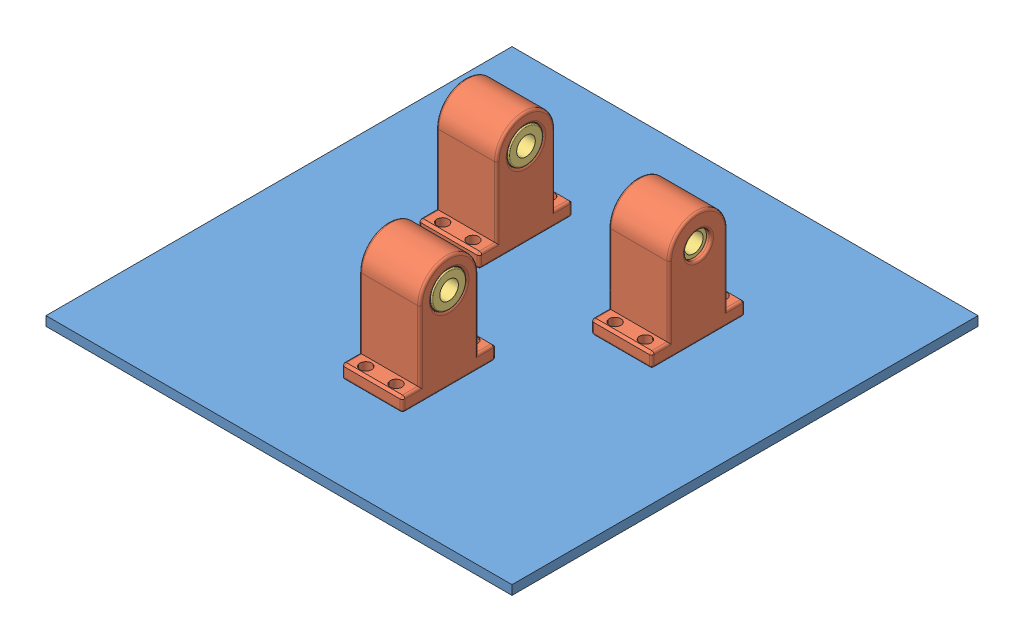
SolidWorks assembly millingBed, configuration Default. Lengths in mm.
Overall size (200 52.5 200).
10 component instances, 3 part files, 11 mates.
Components (placement in the parent):
- MillingBed-1: MillingBed [Default] at (-140.9841 198 101.9923) size (200 4 200)
- lm8uu+Holder-1: lm8uu+Holder [Default] at (-52.4841 225.3393 -25.132) x (1 0 0) z (0 0 -1) size (26.01 48.5 40.01)
  - lm8uu_Bearing_Holder-1: lm8uu_Bearing_Holder [Default] at (35.5 -12.6607 2.8758) size (26.01 48.5 40.01)
  - lm8uu_Bearing-1: lm8uu_Bearing [Default] at (35.5 -12.6607 2.8758) x (0 0 -1) z (0 -1 0) size (15 24 15)
- lm8uu+Holder-7: lm8uu+Holder [Default] at (-29.4841 225.3393 -30.8835) x (-1 0 0) z (0 0 1) size (26.01 48.5 40.01)
  - lm8uu_Bearing_Holder-1: lm8uu_Bearing_Holder [Default] at (35.5 -12.6607 2.8758) size (26.01 48.5 40.01)
  - lm8uu_Bearing-1: lm8uu_Bearing [Default] at (35.5 -12.6607 2.8758) x (0 0 -1) z (0 -1 0) size (15 24 15)
- lm8uu+Holder-9: lm8uu+Holder [Default] at (7.5159 225.3393 39.1165) x (-1 0 0) z (0 0 1) size (26.01 48.5 40.01)
  - lm8uu_Bearing_Holder-1: lm8uu_Bearing_Holder [Default] at (35.5 -12.6607 2.8758) size (26.01 48.5 40.01)
  - lm8uu_Bearing-1: lm8uu_Bearing [Default] at (35.5 -12.6607 2.8758) x (0 0 -1) z (0 -1 0) size (15 24 15)
Mates (geometry in assembly coordinates):
- Distance8: distance = 100 mm anti-aligned: plane of lm8uu+Holder-7/lm8uu_Bearing_Holder-1 through (-90.9841 238 -28.0077) normal (-1 0 0); plane of lm8uu+Holder-1/lm8uu_Bearing_Holder-1 through (9.0159 238 -28.0077) normal (1 0 0)
- Coincident25: coincident aligned: plane of lm8uu+Holder-1/lm8uu_Bearing_Holder-1 through (9.0159 208 -15.5077) normal (0 0 1); plane of lm8uu+Holder-7/lm8uu_Bearing_Holder-1 through (-90.9841 238 -15.5077) normal (0 0 1)
- Coincident26: coincident aligned: plane of lm8uu+Holder-1/lm8uu_Bearing_Holder-1 through (9.0159 202 -48.0077) normal (0 -1 0); plane of lm8uu+Holder-7/lm8uu_Bearing_Holder-1 through (-90.9841 202 -8.0077) normal (0 -1 0)
- Coincident33: coincident aligned: plane of lm8uu+Holder-1/lm8uu_Bearing_Holder-1 through (9.0159 202 -48.0077) normal (0 -1 0); plane of lm8uu+Holder-7/lm8uu_Bearing_Holder-1 through (-90.9841 202 -8.0077) normal (0 -1 0)
- Distance13: distance = 50 mm aligned: plane of lm8uu+Holder-1/lm8uu_Bearing_Holder-1 through (9.0159 208 -48.0077) normal (0 0 -1); plane of MillingBed-1 through (-140.9841 202 -98.0077) normal (0 0 -1)
- Distance14: distance = 50 mm aligned: plane of lm8uu+Holder-1/lm8uu_Bearing_Holder-1 through (9.0159 238 -28.0077) normal (1 0 0); plane of MillingBed-1 through (59.0159 202 101.9923) normal (1 0 0)
- Coincident34: coincident anti-aligned: plane of MillingBed-1 through (-140.9841 202 101.9923) normal (0 1 0); plane of lm8uu+Holder-7/lm8uu_Bearing_Holder-1 through (-90.9841 202 -8.0077) normal (0 -1 0)
- Coincident35: coincident: plane of MillingBed-1 through (-140.9841 202 101.9923) normal (0 1 0); plane of lm8uu+Holder-9/lm8uu_Bearing_Holder-1 through (-207.3852 202 61.9923) normal (0 -1 0)
- Parallel2: parallel: plane of lm8uu+Holder-9/lm8uu_Bearing_Holder-1 through (-207.3852 202 21.9923) normal (0 0 -1); plane of lm8uu+Holder-7/lm8uu_Bearing_Holder-1 through (-90.9841 208 -8.0077) normal (0 0 1)
- Distance16: distance = 70 mm: cylinder of lm8uu+Holder-9/lm8uu_Bearing-1 through (-27.9831 238 41.9923) axis (-1 0 0) radius 4; cylinder of lm8uu+Holder-7/lm8uu_Bearing-1 through (-64.9831 238 -28.0077) axis (-1 0 0) radius 4
- Distance19: distance = 87 mm aligned: plane of lm8uu+Holder-9/lm8uu_Bearing_Holder-1 through (-27.9841 238 41.9923) normal (1 0 0); plane of MillingBed-1 through (59.0159 202 101.9923) normal (1 0 0)
